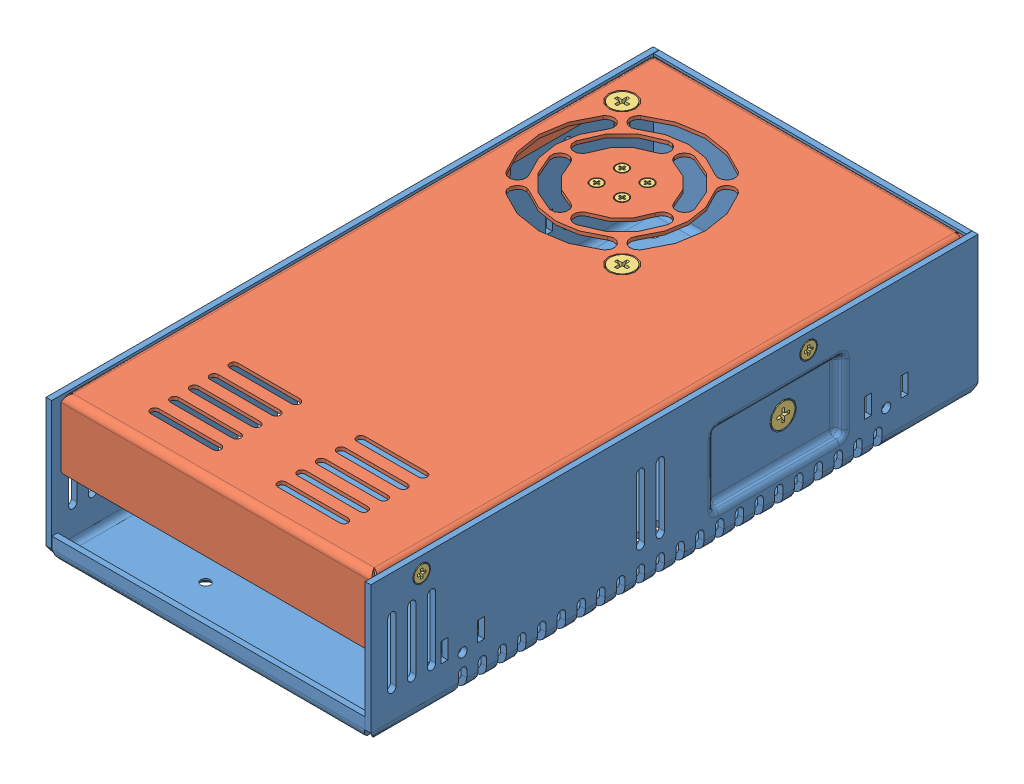
SolidWorks assembly Enclosure of Mean Well QP-320D Quad Power Supply, configuration Default. Lengths in mm.
Overall size (115.1 50.01 215.37).
16 component instances, 3 part files, 17 mates.
Components (placement in the parent):
- Bottom of Enclosure of Mean Well QP-320D Quad Power Supply-1: Bottom of Enclosure of Mean Well QP-320D Quad Power Supply [Default] at (-42.7955 -32.6738 29.1784) size (115.04 49.51 215.36)
- Top of Enclosure of Mean Well QP-320D Quad Power Supply-1: Top of Enclosure of Mean Well QP-320D Quad Power Supply [Default] at (-42.7955 14.1262 28.7784) x (1 0 0) z (0 0 -1) size (110.84 24 209.81)
- flat head screw_am-17: flat head screw_am [B18.6.7M - M3 x 0.5 x 5 Type I Cross Recessed FHMS --5N] at (14.7545 9.3262 118.6784) x (-1 0 0) z (0 0 -1) size (5 5.5 5.5)
- flat head screw_am-18: flat head screw_am [B18.6.7M - M3 x 0.5 x 5 Type I Cross Recessed FHMS --5N] at (14.7545 9.3262 -18.3216) x (-1 0 0) z (0 0 -1) size (5 5.5 5.5)
- flat head screw_am-5: flat head screw_am [B18.6.7M - M4 x 0.7 x 8 Type I Cross Recessed FHMS --8N] at (11.7045 -9.1738 -12.3216) x (-1 0 0) z (0 0 -1) size (8 8.4 8.4)
- flat head screw_am-6: flat head screw_am [B18.6.7M - M4 x 0.7 x 8 Type I Cross Recessed FHMS --8N] at (-29.5256 -9.1738 -75.3216) x (0 0 1) z (-1 0 0) size (8 8.4 8.4)
- flat head screw_am-7: flat head screw_am [B18.6.7M - M3 x 0.5 x 5 Type I Cross Recessed FHMS --5N] at (2.4545 9.3262 -78.3716) x (0 0 1) z (-1 0 0) size (5 5.5 5.5)
- flat head screw_am-8: flat head screw_am [B18.6.7M - M3 x 0.5 x 5 Type I Cross Recessed FHMS --5N] at (-88.0455 9.3262 -78.3716) x (0 0 1) z (-1 0 0) size (5 5.5 5.5)
- flat head screw_am-9: flat head screw_am [B18.6.7M - M3 x 0.5 x 5 Type I Cross Recessed FHMS --5N] at (-100.3455 9.3262 -18.3216) size (5 5.5 5.5)
- flat head screw_am-10: flat head screw_am [B18.6.7M - M3 x 0.5 x 5 Type I Cross Recessed FHMS --5N] at (-100.3455 9.3262 118.6784) size (5 5.5 5.5)
- flat head screw_am-11: flat head screw_am [B18.6.7M - M4 x 0.7 x 8 Type I Cross Recessed FHMS --8N] at (-88.5955 15.3262 -55.6216) x (0 -1 0) z (0 0 1) size (8 8.4 8.4)
- flat head screw_am-12: flat head screw_am [B18.6.7M - M4 x 0.7 x 8 Type I Cross Recessed FHMS --8N] at (-38.5955 15.3262 -5.6216) x (0 -1 0) z (0 0 1) size (8 8.4 8.4)
- flat head screw_am-13: flat head screw_am [B18.6.7M - M2 x 0.4 x 3 Type I Cross Recessed FHMS --3N] at (-68.0955 15.3262 -35.1216) x (0 -1 0) z (0 0 1) size (3 3.8 3.8)
- flat head screw_am-14: flat head screw_am [B18.6.7M - M2 x 0.4 x 3 Type I Cross Recessed FHMS --3N] at (-59.0955 15.3262 -35.1216) x (0 -1 0) z (0 0 1) size (3 3.8 3.8)
- flat head screw_am-15: flat head screw_am [B18.6.7M - M2 x 0.4 x 3 Type I Cross Recessed FHMS --3N] at (-59.0955 15.3262 -26.1216) x (0 -1 0) z (0 0 1) size (3 3.8 3.8)
- flat head screw_am-16: flat head screw_am [B18.6.7M - M2 x 0.4 x 3 Type I Cross Recessed FHMS --3N] at (-68.0955 15.3262 -26.1216) x (0 -1 0) z (0 0 1) size (3 3.8 3.8)
Mates (geometry in assembly coordinates):
- Coincident5: coincident aligned: cone of Bottom of Enclosure of Mean Well QP-320D Quad Power Supply-1 through (14.7045 9.3262 118.6784) axis (-1 0 0); cone of flat head screw_am-17 through (14.3045 9.3262 118.6784) axis (-1 0 0)
- Coincident6: coincident aligned: cone of Bottom of Enclosure of Mean Well QP-320D Quad Power Supply-1 through (14.7045 9.3262 -18.3216) axis (-1 0 0); cone of flat head screw_am-18 through (14.3045 9.3262 -18.3216) axis (-1 0 0)
- Coincident9: coincident aligned: cone of Bottom of Enclosure of Mean Well QP-320D Quad Power Supply-1 through (11.7045 -9.1738 -12.3216) axis (-1 0 0); cone of flat head screw_am-5 through (11.2045 -9.1738 -12.3216) axis (-1 0 0)
- Coincident10: coincident aligned: cone of Bottom of Enclosure of Mean Well QP-320D Quad Power Supply-1 through (-29.5256 -9.1738 -75.3216) axis (0 0 1); cone of flat head screw_am-6 through (-29.5256 -9.1738 -74.8216) axis (0 0 1)
- Coincident11: coincident aligned: cone of Bottom of Enclosure of Mean Well QP-320D Quad Power Supply-1 through (2.4545 9.3262 -78.3216) axis (0 0 1); cone of flat head screw_am-7 through (2.4545 9.3262 -77.9216) axis (0 0 1)
- Coincident12: coincident aligned: cone of Bottom of Enclosure of Mean Well QP-320D Quad Power Supply-1 through (-88.0455 9.3262 -78.3216) axis (0 0 1); cone of flat head screw_am-8 through (-88.0455 9.3262 -77.9216) axis (0 0 1)
- Coincident15: coincident aligned: cone of Bottom of Enclosure of Mean Well QP-320D Quad Power Supply-1 through (-100.2955 9.3262 -18.3216) axis (1 0 0); cone of flat head screw_am-9 through (-99.8955 9.3262 -18.3216) axis (1 0 0)
- Coincident16: coincident aligned: cone of Bottom of Enclosure of Mean Well QP-320D Quad Power Supply-1 through (-100.2955 9.3262 118.6784) axis (1 0 0); cone of flat head screw_am-10 through (-99.8955 9.3262 118.6784) axis (1 0 0)
- Concentric9: concentric anti-aligned: cylinder of Top of Enclosure of Mean Well QP-320D Quad Power Supply-1 through (-98.0455 9.3262 118.6784) axis (-1 0 0) radius 1.25; cylinder of flat head screw_am-17 through (21.1045 9.3262 118.6784) axis (1 0 0) radius 1.5
- Concentric10: concentric anti-aligned: cylinder of Top of Enclosure of Mean Well QP-320D Quad Power Supply-1 through (-98.0455 9.3262 -18.3216) axis (-1 0 0) radius 1.25; cylinder of flat head screw_am-18 through (21.1045 9.3262 -18.3216) axis (1 0 0) radius 1.5
- Width1: width anti-aligned: plane of Bottom of Enclosure of Mean Well QP-320D Quad Power Supply-1 through (-98.2955 -32.6738 29.1784) normal (1 0 0); plane of Bottom of Enclosure of Mean Well QP-320D Quad Power Supply-1 through (12.7045 -32.6738 29.1784) normal (-1 0 0); plane of Top of Enclosure of Mean Well QP-320D Quad Power Supply-1 through (-98.0455 14.1262 28.7784) normal (-1 0 0); plane of Top of Enclosure of Mean Well QP-320D Quad Power Supply-1 through (12.4545 14.1262 28.7784) normal (1 0 0)
- Coincident17: coincident aligned: cone of Top of Enclosure of Mean Well QP-320D Quad Power Supply-1 through (-88.5955 15.3262 -55.6216) axis (0 -1 0); cone of flat head screw_am-11 through (-88.5955 14.8262 -55.6216) axis (0 -1 0)
- Coincident18: coincident aligned: cone of Top of Enclosure of Mean Well QP-320D Quad Power Supply-1 through (-38.5955 15.3262 -5.6216) axis (0 -1 0); cone of flat head screw_am-12 through (-38.5955 14.8262 -5.6216) axis (0 -1 0)
- Coincident19: coincident aligned: cone of Top of Enclosure of Mean Well QP-320D Quad Power Supply-1 through (-68.0955 15.3262 -35.1216) axis (0 -1 0); cone of flat head screw_am-13 through (-68.0955 15.0262 -35.1216) axis (0 -1 0)
- Coincident20: coincident aligned: cone of Top of Enclosure of Mean Well QP-320D Quad Power Supply-1 through (-59.0955 15.3262 -35.1216) axis (0 -1 0); cone of flat head screw_am-14 through (-59.0955 15.0262 -35.1216) axis (0 -1 0)
- Coincident21: coincident aligned: cone of Top of Enclosure of Mean Well QP-320D Quad Power Supply-1 through (-59.0955 15.3262 -26.1216) axis (0 -1 0); cone of flat head screw_am-15 through (-59.0955 15.0262 -26.1216) axis (0 -1 0)
- Coincident22: coincident aligned: cone of Top of Enclosure of Mean Well QP-320D Quad Power Supply-1 through (-68.0955 15.3262 -26.1216) axis (0 -1 0); cone of flat head screw_am-16 through (-68.0955 15.0262 -26.1216) axis (0 -1 0)
